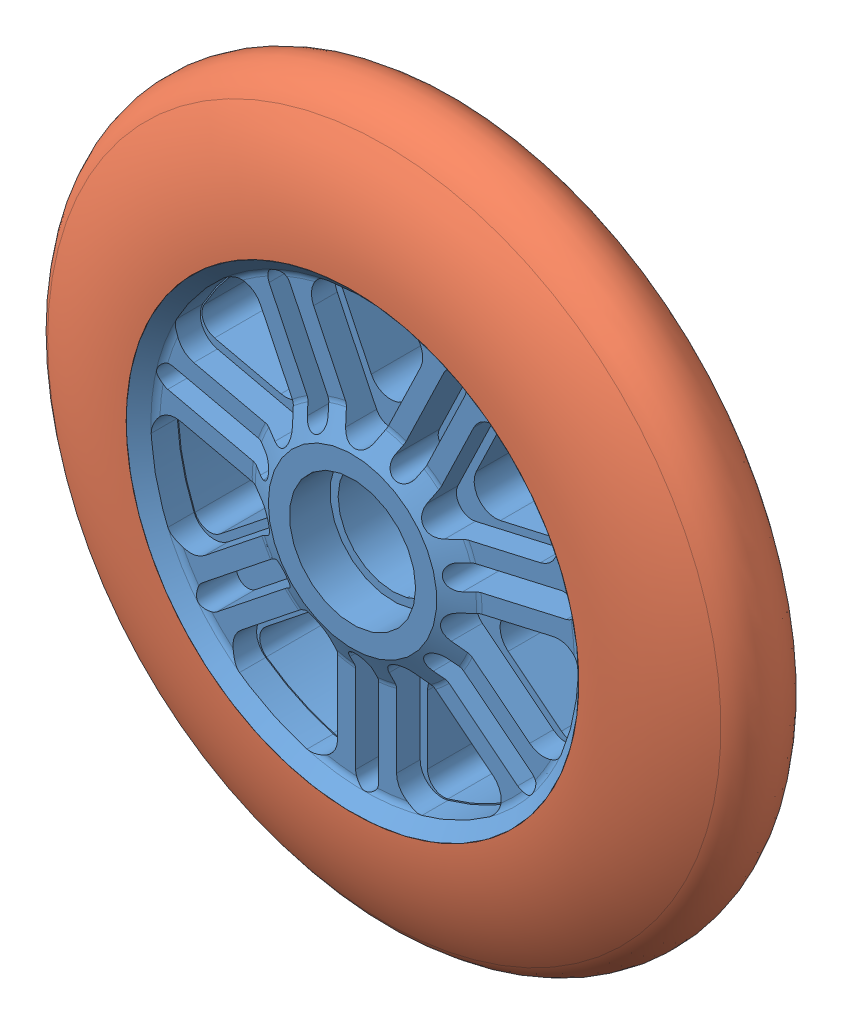
SolidWorks assembly Skate Wheel (Servo City 595626), configuration Default. Lengths in mm.
Overall size (124.46 124.46 23.93).
2 component instances, 2 part files, 0 mates.
Components (placement in the parent):
- 595626 pt1-1: 595626 pt1 [Default] at (-97.3782 16.9772 39.8511) size (101.6 101.6 23.93)
- 595626 pt2-1: 595626 pt2 [Default] at (-97.3782 16.9772 39.8511) size (124.46 124.46 23.93)
